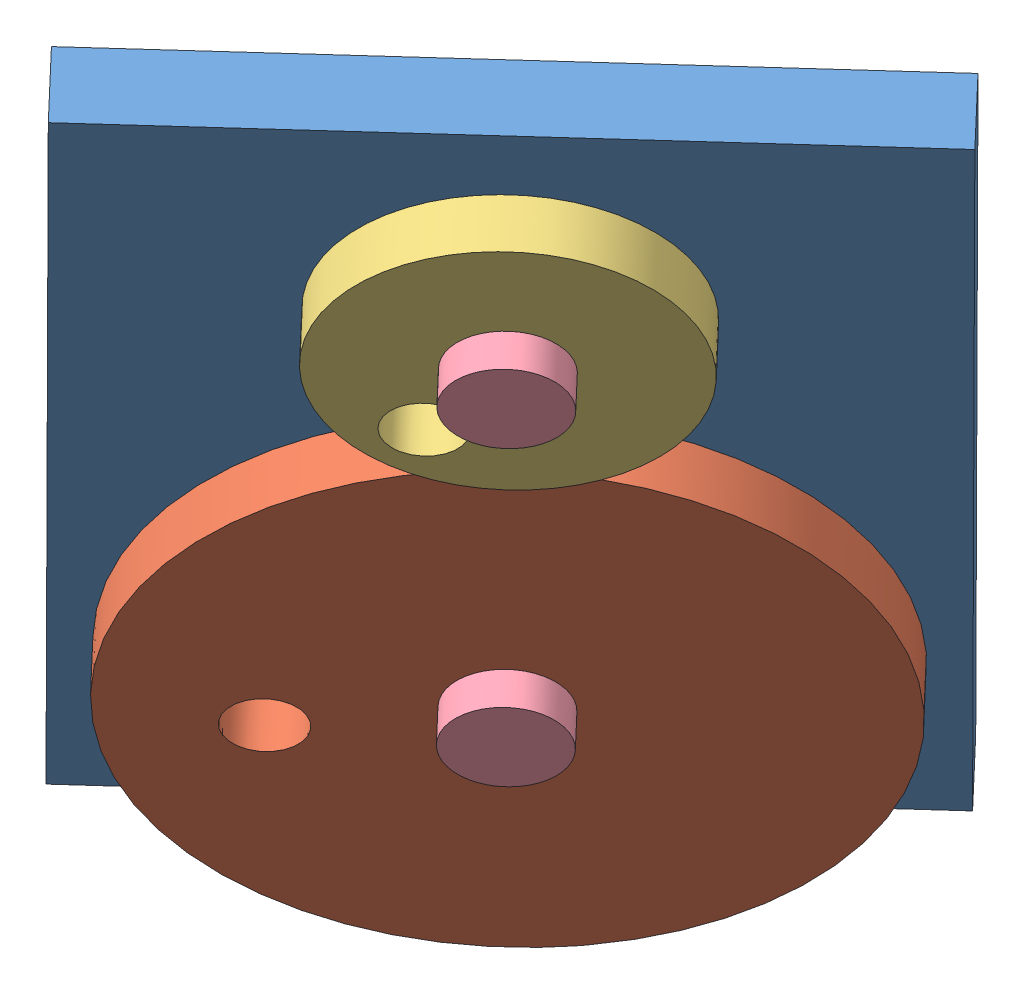
SolidWorks assembly ansamblu, configuration Default. Lengths in mm.
Overall size (43.83 58.59 42.12).
5 component instances, 4 part files, 9 mates.
Components (placement in the parent):
- baza-1: baza [Default] at (-4.6926 1.7777 0.2944) x (0.24246 0.940091 0.239672) z (-0.728759 0.013409 0.684639) size (50 4 40)
- roata_mare-1: roata_mare [Default] at (-22.6622 -11.1154 10.6317) x (-0.119164 -0.929469 -0.349124) z (-0.758733 -0.141556 0.635835) size (36 4 36)
- roata_mica-1: roata_mica [Default] at (-15.4753 13.9264 17.7912) x (0.425677 -0.588564 -0.687307) z (-0.639277 -0.733173 0.23191) size (18 4 18)
- bolt-1: bolt [Default] at (-20.7409 -12.1374 12.6968) x (-0.365836 -0.923346 -0.116602) z (0.675307 -0.177151 -0.715945) size (6 11 6)
- bolt-2: bolt [Default] at (-13.5541 12.9044 19.8563) x (-0.432455 -0.900612 -0.043372) z (0.634712 -0.269905 -0.724081) size (6 11 6)
Mates (geometry in assembly coordinates):
- Concentric1: concentric anti-aligned: cylinder of baza-1 through (-63.7483 10.74 -33.5301) axis (0.640409 -0.340661 0.68835) radius 1.5; cylinder of roata_mare-1 through (9.4022 -28.1718 45.0965) axis (-0.640409 0.340661 -0.68835) radius 1.5
- Coincident1: coincident anti-aligned: plane of baza-1 through (-10.7541 -21.7246 -5.6974) normal (0.640409 -0.340661 0.68835); plane of roata_mare-1 through (-22.6622 -11.1154 10.6317) normal (-0.640409 0.340661 -0.68835)
- Concentric2: concentric anti-aligned: cylinder of baza-1 through (-57.2019 36.1225 -27.059) axis (0.640409 -0.340661 0.68835) radius 1.5; cylinder of roata_mica-1 through (0.3864 5.4888 34.8404) axis (-0.640409 0.340661 -0.68835) radius 1.5
- Coincident2: coincident anti-aligned: plane of baza-1 through (-10.7541 -21.7246 -5.6974) normal (0.640409 -0.340661 0.68835); plane of roata_mica-1 through (-16.1158 14.267 17.1029) normal (-0.640409 0.340661 -0.68835)
- Coincident3: coincident anti-aligned: plane of bolt-2 through (-13.5541 12.9044 19.8563) normal (-0.640409 0.340661 -0.68835); plane of roata_mica-1 through (-13.5541 12.9044 19.8563) normal (0.640409 -0.340661 0.68835)
- Concentric4: concentric anti-aligned: cylinder of roata_mica-1 through (0.3864 5.4888 34.8404) axis (-0.640409 0.340661 -0.68835) radius 1.5; cylinder of bolt-2 through (-19.3178 15.9703 13.6611) axis (0.640409 -0.340661 0.68835) radius 1.5
- Coincident4: coincident anti-aligned: plane of roata_mare-1 through (-20.7409 -12.1374 12.6968) normal (0.640409 -0.340661 0.68835); plane of bolt-1 through (-20.7409 -12.1374 12.6968) normal (-0.640409 0.340661 -0.68835)
- Concentric5: concentric anti-aligned: cylinder of roata_mare-1 through (9.4022 -28.1718 45.0965) axis (-0.640409 0.340661 -0.68835) radius 1.5; cylinder of bolt-1 through (-26.5046 -9.0715 6.5016) axis (0.640409 -0.340661 0.68835) radius 1.5
- GearMate1: gear = 0.018 : 0.036: cylinder of roata_mare-1 through (-20.7409 -12.1374 12.6968) axis (-0.640409 0.340661 -0.68835) radius 18; cylinder of roata_mica-1 through (-13.5541 12.9044 19.8563) axis (-0.640409 0.340661 -0.68835) radius 9
